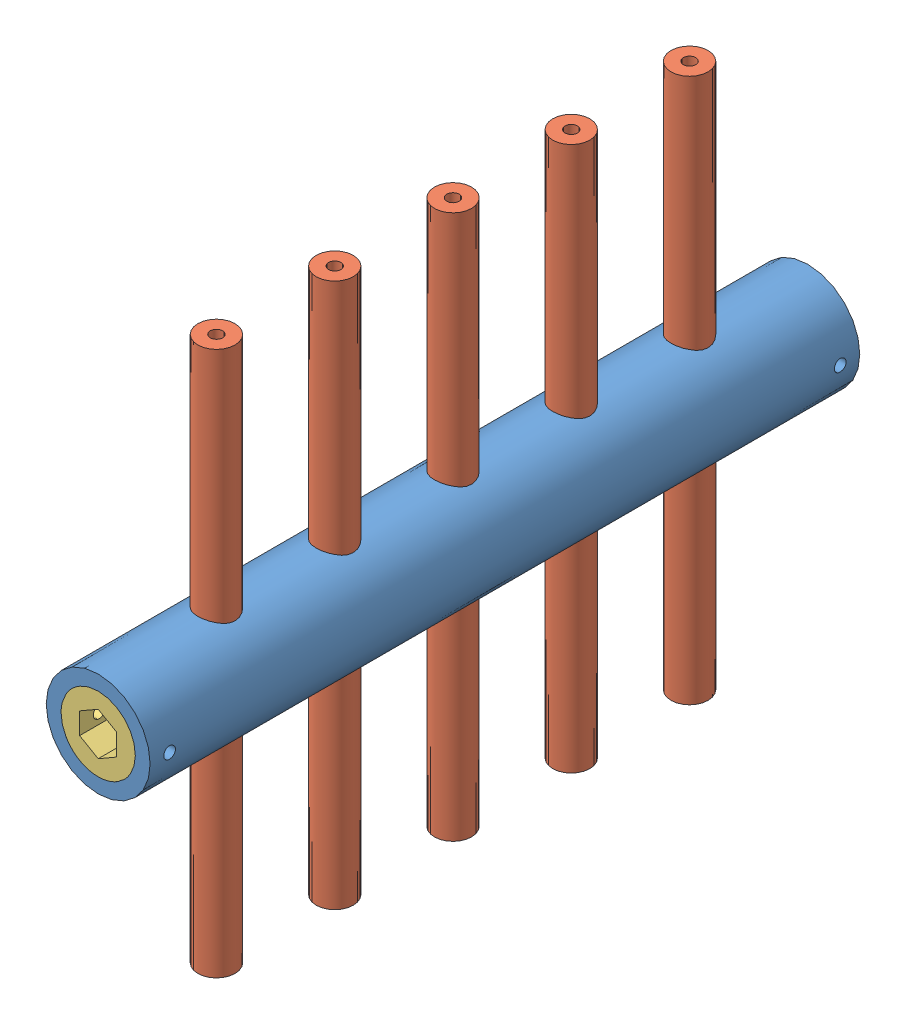
SolidWorks assembly Sweeper, configuration Default. Lengths in mm.
Overall size (26.67 139.7 182.12).
10 component instances, 5 part files, 22 mates.
Components (placement in the parent):
- PVC-1: PVC [Default] at (58.8928 106.2928 45.8817) size (26.67 26.67 182.12)
- Part4^Sweeper-1: Part4^Sweeper [Default] at origin (virtual)
- Part10^Sweeper-1: Part10^Sweeper [Default] at origin (virtual)
- NoodleShort-1: NoodleShort [Default] at (58.8928 179.9456 197.6467) x (1 0 -0.00013) z (0 -1 0) size (9.53 9.53 139.7)
- NoodleShort-2: NoodleShort [Default] at (58.8928 179.9456 167.2937) x (1 0 -0.00013) z (0 -1 0) size (9.53 9.53 139.7)
- NoodleShort-3: NoodleShort [Default] at (58.8928 179.9456 136.9407) x (0.999629 0 -0.027255) z (0 -1 0) size (9.53 9.53 139.7)
- NoodleShort-4: NoodleShort [Default] at (58.8928 179.9456 106.5877) x (1 0 -0.00013) z (0 -1 0) size (9.53 9.53 139.7)
- NoodleShort-5: NoodleShort [Default] at (58.8928 179.9456 76.2347) x (1 0 -0.00013) z (0 -1 0) size (9.53 9.53 139.7)
- pvcHub-1: pvcHub [Default] at (58.8928 106.2928 45.8817) x (0 1 0) z (0 0 1) size (19.05 19.05 10)
- pvcHub-2: pvcHub [Default] at (58.8928 106.2928 217.9997) x (0 1 0) z (0 0 1) size (19.05 19.05 10)
Mates (geometry in assembly coordinates):
- Concentric1: concentric: cylinder of PVC-1 through (58.8928 119.6278 197.6467) axis (0 -1 0) radius 3.175; cylinder of ? through (58.8928 -16.8918 197.6467) axis (0 1 0) radius 4.7625
- Concentric2: concentric: cylinder of PVC-1 through (58.8928 119.6278 167.2937) axis (0 -1 0) radius 3.175; cylinder of ? through (58.8928 -16.8918 167.2937) axis (0 1 0) radius 4.7625
- Concentric3: concentric: cylinder of PVC-1 through (58.8928 119.6278 136.9407) axis (0 -1 0) radius 3.175; cylinder of ? through (58.8928 -16.8918 136.9407) axis (0 1 0) radius 4.7625
- Concentric4: concentric: cylinder of PVC-1 through (58.8928 119.6278 106.5877) axis (0 -1 0) radius 3.175; cylinder of ? through (58.8928 -16.8918 106.5877) axis (0 1 0) radius 4.7625
- Concentric5: concentric: cylinder of PVC-1 through (58.8928 119.6278 76.2347) axis (0 -1 0) radius 3.175; cylinder of ? through (58.8928 -16.8918 76.2347) axis (0 1 0) radius 4.7625
- Coincident1: coincident: plane of ? through (58.8928 199.0082 197.6467) normal (0 1 0); plane of ? through (58.8928 199.0082 167.2937) normal (0 1 0)
- Coincident2: coincident: plane of ? through (58.8928 199.0082 167.2937) normal (0 1 0); plane of ? through (58.8928 199.0082 136.9407) normal (0 1 0)
- Coincident3: coincident: plane of ? through (58.8928 199.0082 136.9407) normal (0 1 0); plane of ? through (58.8928 199.0082 106.5877) normal (0 1 0)
- Coincident4: coincident: plane of ? through (58.8928 199.0082 106.5877) normal (0 1 0); plane of ? through (58.8928 199.0082 76.2347) normal (0 1 0)
- Concentric6: concentric: cylinder of PVC-1 through (58.8928 119.6278 197.6467) axis (0 -1 0) radius 3.175; cylinder of NoodleShort-1 through (58.8928 40.2456 197.6467) axis (0 1 0) radius 4.7625
- Concentric7: concentric: cylinder of PVC-1 through (58.8928 119.6278 167.2937) axis (0 -1 0) radius 3.175; cylinder of NoodleShort-2 through (58.8928 40.2456 167.2937) axis (0 1 0) radius 4.7625
- Concentric8: concentric: cylinder of PVC-1 through (58.8928 119.6278 136.9407) axis (0 -1 0) radius 3.175; cylinder of NoodleShort-3 through (58.8928 40.2456 136.9407) axis (0 1 0) radius 4.7625
- Concentric9: concentric: cylinder of PVC-1 through (58.8928 119.6278 106.5877) axis (0 -1 0) radius 3.175; cylinder of NoodleShort-4 through (58.8928 40.2456 106.5877) axis (0 1 0) radius 4.7625
- Concentric10: concentric: cylinder of PVC-1 through (58.8928 119.6278 76.2347) axis (0 -1 0) radius 3.175; cylinder of NoodleShort-5 through (58.8928 40.2456 76.2347) axis (0 1 0) radius 4.7625
- Coincident5: coincident: plane of NoodleShort-1 through (58.8928 179.9456 197.6467) normal (0 1 0); plane of NoodleShort-2 through (58.8928 179.9456 167.2937) normal (0 1 0)
- Coincident6: coincident: plane of NoodleShort-2 through (58.8928 179.9456 167.2937) normal (0 1 0); plane of NoodleShort-3 through (58.8928 179.9456 136.9407) normal (0 1 0)
- Coincident7: coincident: plane of NoodleShort-3 through (58.8928 179.9456 136.9407) normal (0 1 0); plane of NoodleShort-4 through (58.8928 179.9456 106.5877) normal (0 1 0)
- Coincident8: coincident: plane of NoodleShort-4 through (58.8928 179.9456 106.5877) normal (0 1 0); circle of NoodleShort-5
- Concentric11: concentric: cylinder of PVC-1 through (45.5578 106.2928 222.9997) axis (1 0 0) radius 1.5; cylinder of pvcHub-2 through (68.4178 106.2928 222.9997) axis (-1 0 0) radius 1.5
- Concentric12: concentric: cylinder of PVC-1 through (45.5578 106.2928 50.8817) axis (1 0 0) radius 1.5; cylinder of pvcHub-1 through (68.4178 106.2928 50.8817) axis (-1 0 0) radius 1.5
- Concentric13: concentric: cylinder of PVC-1 through (58.8928 106.2928 227.9997) axis (0 0 -1) radius 9.525; cylinder of pvcHub-1 through (58.8928 106.2928 55.8817) axis (0 0 -1) radius 9.525
- Concentric14: concentric: cylinder of PVC-1 through (58.8928 106.2928 227.9997) axis (0 0 -1) radius 13.335; cylinder of pvcHub-2 through (58.8928 106.2928 227.9997) axis (0 0 -1) radius 9.525
